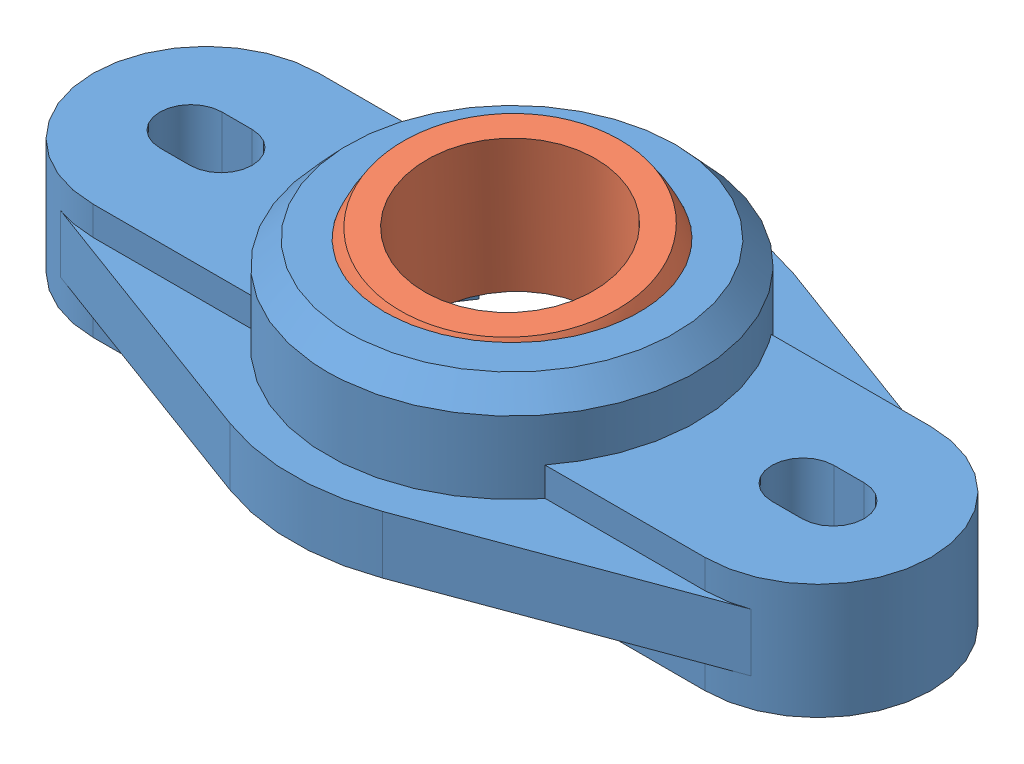
SolidWorks assembly Assem2, configuration Default. Lengths in mm.
Overall size (72.61 19.35 38).
2 component instances, 2 part files, 1 mates.
Components (placement in the parent):
- Bearing_Igus_EFOI-10R-1: Bearing_Igus_EFOI-10R [Default] at (31.8431 39.3288 52.255) size (72.61 15.75 38)
- Ball_Igus_EFOI_10R-1: Ball_Igus_EFOI_10R [Default] at (31.8431 45.3296 52.255) x (0.355897 0.067105 -0.932113) z (0.073493 0.99232 0.099501) size (24 24 12.7)
Mates (geometry in assembly coordinates):
- Concentric1: concentric: sphere of Bearing_Igus_EFOI-10R-1; sphere of Ball_Igus_EFOI_10R-1
